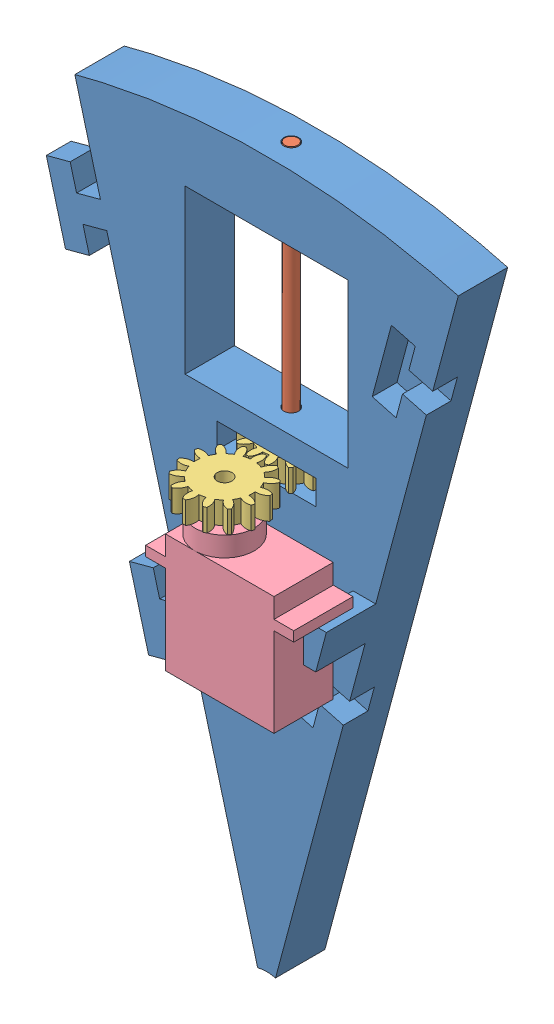
SolidWorks assembly proto_servo, configuration Default. Lengths in mm.
Overall size (83.42 143.29 33.73).
5 component instances, 4 part files, 10 mates.
Components (placement in the parent):
- sihverplaat_servo-1: sihverplaat_servo [Default] at (7.1676 178.6045 270.754) size (83.42 143.29 20)
- numbriplaat_shaft-1: numbriplaat_shaft [Default] at (7.1676 268.6607 270.754) size (2.6 60 2.6)
- spur gear_am-6: spur gear_am [Metric - Spur gear 1M 14T 14.5PA 4.5mmFW ---S14N75H50L3N] at (7.1676 272.6045 270.754) x (0 1 0) z (0.994793 0 -0.101917) size (4.5 15.72 16)
- spur gear_am-8: spur gear_am [Metric - Spur gear 1M 14T 14.5PA 4.5mmFW ---S14N75H50L3N] at (7.6676 277.1045 284.754) x (0 -1 0) z (-0.79797 0 0.602697) size (4.5 15.72 16)
- servo-1: servo [Default] at (12.6676 255.1045 278.754) size (30 31 12)
Mates (geometry in assembly coordinates):
- Concentric1: concentric aligned: cylinder of sihverplaat_servo-1 through (7.1676 273.6045 270.754) axis (0 1 0) radius 1.5; circle of numbriplaat_shaft-1
- Concentric6: concentric anti-aligned: cylinder of numbriplaat_shaft-1 through (7.1676 328.6607 270.754) axis (0 -1 0) radius 1.3; circle of spur gear_am-6
- Coincident2: coincident anti-aligned: plane of sihverplaat_servo-1 through (17.1676 277.1045 275.755) normal (0 -1 0); plane of spur gear_am-6 through (7.1676 277.1045 270.754) normal (0 1 0)
- Parallel2: parallel anti-aligned: plane of spur gear_am-6 through (7.1676 277.1045 270.754) normal (0 1 0); plane of spur gear_am-8 through (7.6676 272.6045 284.754) normal (0 -1 0)
- Coincident5: coincident anti-aligned: plane of sihverplaat_servo-1 through (17.1676 277.1045 275.755) normal (0 -1 0); plane of spur gear_am-8 through (7.6676 277.1045 284.754) normal (0 1 0)
- Concentric7: concentric anti-aligned: circle of spur gear_am-8; circle of servo-1
- Distance1: distance = 3 mm anti-aligned: plane of sihverplaat_servo-1 through (7.1676 178.6045 275.754) normal (0 0 1); plane of servo-1 through (12.6676 255.1045 278.754) normal (0 0 -1)
- Distance2: distance = 11 mm anti-aligned: plane of sihverplaat_servo-1 through (-9.3324 282.1045 275.754) normal (1 0 0); plane of servo-1 through (1.6676 243.1045 290.754) normal (-1 0 0)
- GearMate3: gear = 14 : 14 mm: circle of spur gear_am-6; circle of spur gear_am-8
- Coincident6: coincident anti-aligned: plane of sihverplaat_servo-1 through (7.1676 261.1045 285.754) normal (0 1 0); plane of servo-1 through (27.6676 261.1045 278.754) normal (0 -1 0)
